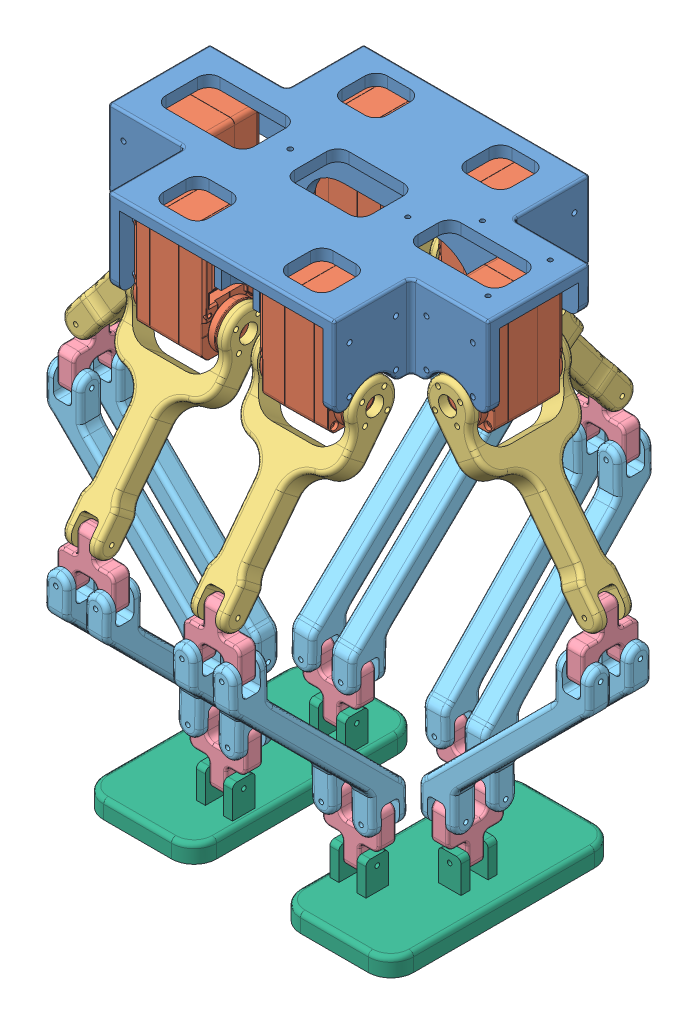
SolidWorks assembly bluebody-urdf, configuration Default. Lengths in mm.
Overall size (254.56 248.23 199.52).
42 component instances, 6 part files, 75 mates.
Components (placement in the parent):
- link0-1: link0 [Default] x (1 0 0) z (0 0 -1) size (168 59.68 113)
  - platform-v4-1: platform-v4 [Default] at (0 36.8 -17.5) x (-1 0 0) z (0 0 1) size (168 36.8 113)
  - Servo-LX-16A-1: Servo-LX-16A [Default] at (37.5 14.825 39.5) x (0 -1 0) z (0 0 1) size (54.66 37.3 26.46)
  - Servo-LX-16A-2: Servo-LX-16A [Default] at (-37.5 14.825 39.5) x (0 -1 0) z (0 0 -1) size (54.66 37.3 26.46)
  - Servo-LX-16A-3: Servo-LX-16A [Default] at (-67 14.825 -10) x (0 -1 0) z (1 0 0) size (54.66 37.3 26.46)
  - Servo-LX-16A-4: Servo-LX-16A [Default] at (-37.5 14.825 -39.5) x (0 -1 0) z (0 0 -1) size (54.66 37.3 26.46)
  - Servo-LX-16A-5: Servo-LX-16A [Default] at (37.5 14.825 -39.5) x (0 -1 0) z (0 0 1) size (54.66 37.3 26.46)
  - Servo-LX-16A-6: Servo-LX-16A [Default] at (67 14.825 -10) x (0 -1 0) z (1 0 0) size (54.66 37.3 26.46)
- link1-1: link1 [Default] at (27.9 -74.503 60.6628) x (0 0.793607 -0.60843) z (1 0 0) size (96 20 46.12)
- link1-2: link1 [Default] at (88.1738 -74.4962 0.4) x (-0.608687 0.793411 0) z (0 0 -1) size (96 20 46.12)
- link1-3: link1 [Default] at (27.9 -74.503 -60.6628) x (0 0.793607 0.60843) z (-1 0 0) size (96 20 46.12)
- link1-4: link1 [Default] at (-27.9 -74.503 -60.6628) x (0 0.793607 0.60843) z (-1 0 0) size (96 20 46.12)
- link1-5: link1 [Default] at (-88.1738 -74.4962 0.4) x (0.608687 0.793411 0) z (0 0 1) size (96 20 46.12)
- link1-6: link1 [Default] at (-27.9 -74.503 60.6628) x (0 0.793607 -0.60843) z (1 0 0) size (96 20 46.12)
- link2-1: link2 [Default] at (27.9 -108.2473 85) x (1 0 0) z (0 0 -1) size (25.2 28 7.6)
- link2-2: link2 [Default] at (112.5213 -108.2326 0.4) x (0 0 1) z (1 0 0) size (25.2 28 7.6)
- link2-3: link2 [Default] at (27.9 -108.2473 -85) x (1 0 0) z (0 0 -1) size (25.2 28 7.6)
- link2-4: link2 [Default] at (-27.9 -108.2473 -85) x (1 0 0) z (0 0 -1) size (25.2 28 7.6)
- link2-5: link2 [Default] at (-112.5213 -108.2326 0.4) x (0 0 -1) z (-1 0 0) size (25.2 28 7.6)
- link2-6: link2 [Default] at (-27.9 -108.2473 85) x (1 0 0) z (0 0 -1) size (25.2 28 7.6)
- link3-1: link3 [Default] at (14.9116 -168.336 55) x (0 0 -1) z (0.999814 0.019301 0) size (76 94 10)
- link3-2: link3 [Default] at (32.5116 -168.336 55) x (0 0 1) z (0.999814 0.019301 0) size (76 94 10)
- link3-3: link3 [Default] at (82.5213 -168.2559 13.9999) x (-1 0 0) z (0 0.004762 -0.999989) size (76 94 10)
- link3-4: link3 [Default] at (82.5213 -168.2559 -3.6001) x (1 0 0) z (0 0.004762 -0.999989) size (76 94 10)
- link3-5: link3 [Default] at (42.5097 -168.143 -55) x (0 0 -1) z (-0.999814 -0.019301 0) size (76 94 10)
- link3-6: link3 [Default] at (24.9097 -168.143 -55) x (0 0 -1) z (-0.999814 -0.019301 0) size (76 94 10)
- link3-7: link3 [Default] at (-14.9116 -168.336 -55) x (0 0 1) z (-0.999814 0.019301 0) size (76 94 10)
- link3-8: link3 [Default] at (-32.5116 -168.336 -55) x (0 0 1) z (-0.999814 0.019301 0) size (76 94 10)
- link3-9: link3 [Default] at (-82.5213 -168.2083 -13.5999) x (1 0 0) z (0 -0.004762 0.999989) size (76 94 10)
- link3-10: link3 [Default] at (-82.5213 -168.2083 4.0001) x (1 0 0) z (0 -0.004762 0.999989) size (76 94 10)
- link3-11: link3 [Default] at (-42.5097 -168.143 55) x (0 0 -1) z (0.999814 -0.019301 0) size (76 94 10)
- link3-12: link3 [Default] at (-24.9097 -168.143 55) x (0 0 -1) z (0.999814 -0.019301 0) size (76 94 10)
- bluefeet-1: bluefeet [Default] at (43.5213 -248.2317 0) x (0 0 -1) z (1 0 0) size (100 41.94 54.92) (flexible)
  - feet-1: feet [Default] at origin size (100 22 50)
  - link2-1: link2 [Default] at (-25 20 -14) x (0 0 -1) z (1 0 0) size (25.2 28 7.6)
  - link2-2: link2 [Default] at (0 20 9) size (25.2 28 7.6)
  - link2-3: link2 [Default] at (25 20 -14) x (0 0 -1) z (1 0 0) size (25.2 28 7.6)
- bluefeet-2: bluefeet [Default] at (-43.5213 -248.2317 0) x (0 0 1) z (-1 0 0) size (100 41.94 54.92) (flexible)
  - feet-1: feet [Default] at origin size (100 22 50)
  - link2-1: link2 [Default] at (-25 20 -14) x (0 0 -1) z (1 0 0) size (25.2 28 7.6)
  - link2-2: link2 [Default] at (0 20 9) size (25.2 28 7.6)
  - link2-3: link2 [Default] at (25 20 -14) x (0 0 -1) z (1 0 0) size (25.2 28 7.6)
Mates (geometry in assembly coordinates):
- Coincident1: coincident aligned: plane of link0-1/platform-v4-1 through (0 0 17.5) normal (0 1 0)
- Coincident2: coincident anti-aligned: plane of link0-1/platform-v4-1 through (0 -36.8 17.5) normal (-1 0 0)
- Coincident4: coincident anti-aligned: plane of link0-1/platform-v4-1 through (0 -36.8 0) normal (0 0 -1)
- Concentric1: concentric aligned: cylinder of link0-1/Servo-LX-16A-5 through (46.6 -40.325 39.5) axis (1 0 0) radius 10; cylinder of link1-1 through (4.9 -40.325 39.5) axis (1 0 0) radius 4
- Distance1: distance = 0.9 mm anti-aligned: plane of link0-1/Servo-LX-16A-5 through (46 -29.3267 39.5) normal (1 0 0); plane of link1-1 through (46.9 -60.5091 78.9158) normal (-1 0 0)
- Concentric2: concentric anti-aligned: cylinder of link0-1/Servo-LX-16A-6 through (67 -40.325 -14.6) axis (0 0 1) radius 10; cylinder of link1-2 through (67 -40.325 23.4) axis (0 0 -1) radius 4
- Distance2: distance = 0.9 mm anti-aligned: plane of link1-2 through (106.4223 -60.4964 -18.6) normal (0 0 1); plane of link0-1/Servo-LX-16A-6 through (86.9 -79.4276 -17.7) normal (0 0 -1)
- Concentric3: concentric anti-aligned: cylinder of link0-1/Servo-LX-16A-1 through (46.6 -40.325 -39.5) axis (1 0 0) radius 10; cylinder of link1-3 through (50.9 -40.325 -39.5) axis (-1 0 0) radius 4
- Distance3: distance = 0.9 mm anti-aligned: plane of link1-3 through (8.9 -60.5091 -78.9158) normal (1 0 0); plane of link0-1/Servo-LX-16A-1 through (9.8 -79.4276 -59.4) normal (-1 0 0)
- Concentric4: concentric aligned: cylinder of link0-1/Servo-LX-16A-2 through (-46.6 -40.325 -39.5) axis (-1 0 0) radius 10; cylinder of link1-4 through (-4.9 -40.325 -39.5) axis (-1 0 0) radius 4
- Distance4: distance = 0.9 mm anti-aligned: plane of link1-4 through (-8.9 -60.5091 -78.9158) normal (-1 0 0); plane of link0-1/Servo-LX-16A-2 through (-9.8 -79.4276 -19.6) normal (1 0 0)
- Concentric5: concentric aligned: cylinder of link0-1/Servo-LX-16A-3 through (-67 -40.325 19.1) axis (0 0 1) radius 10; cylinder of link1-5 through (-67 -40.325 -22.6) axis (0 0 1) radius 4
- Distance5: distance = 0.9 mm anti-aligned: plane of link1-5 through (-106.4223 -60.4964 -18.6) normal (0 0 1); plane of link0-1/Servo-LX-16A-3 through (-47.1 -79.4276 -17.7) normal (0 0 -1)
- Concentric6: concentric anti-aligned: cylinder of link1-6 through (-50.9 -40.325 39.5) axis (1 0 0) radius 4; cylinder of link0-1/Servo-LX-16A-4 through (-46.6 -40.325 39.5) axis (-1 0 0) radius 10
- Distance6: distance = 0.9 mm anti-aligned: plane of link1-6 through (-8.9 -60.5091 78.9158) normal (-1 0 0); plane of link0-1/Servo-LX-16A-4 through (-9.8 -79.4276 59.4) normal (1 0 0)
- Concentric7: concentric aligned: cylinder of link1-1 through (4.9 -106.2473 85) axis (1 0 0) radius 1; cylinder of link2-1 through (24.1 -106.2473 85) axis (1 0 0) radius 1.15
- Distance7: distance = 0.2 mm anti-aligned: plane of link2-1 through (31.7 -108.2473 88.8) normal (1 0 0); plane of link1-1 through (31.9 -60.5091 78.9158) normal (-1 0 0)
- Concentric8: concentric anti-aligned: cylinder of link1-2 through (112.5213 -106.2326 23.4) axis (0 0 -1) radius 1; cylinder of link2-2 through (112.5213 -106.2326 -3.4) axis (0 0 1) radius 1.15
- Distance8: distance = 0.2 mm anti-aligned: plane of link2-2 through (108.7213 -108.2326 -3.4) normal (0 0 -1); plane of link1-2 through (106.4223 -60.4964 -3.6) normal (0 0 1)
- Concentric9: concentric anti-aligned: cylinder of link1-3 through (50.9 -106.2473 -85) axis (-1 0 0) radius 1; cylinder of link2-3 through (24.1 -106.2473 -85) axis (1 0 0) radius 1.15
- Distance9: distance = 0.2 mm anti-aligned: plane of link2-3 through (31.7 -108.2473 -81.2) normal (1 0 0); plane of link1-3 through (31.9 -60.5091 -78.9158) normal (-1 0 0)
- Concentric10: concentric anti-aligned: cylinder of link1-4 through (-4.9 -106.2473 -85) axis (-1 0 0) radius 1; cylinder of link2-4 through (-31.7 -106.2473 -85) axis (1 0 0) radius 1.15
- Distance10: distance = 0.2 mm anti-aligned: plane of link2-4 through (-31.7 -108.2473 -81.2) normal (-1 0 0); plane of link1-4 through (-31.9 -60.5091 -78.9158) normal (1 0 0)
- Concentric11: concentric anti-aligned: cylinder of link1-5 through (-112.5213 -106.2326 -22.6) axis (0 0 1) radius 1; cylinder of link2-5 through (-112.5213 -106.2326 4.2) axis (0 0 -1) radius 1.15
- Distance11: distance = 0.2 mm anti-aligned: plane of link2-5 through (-108.7213 -108.2326 -3.4) normal (0 0 -1); plane of link1-5 through (-106.4223 -60.4964 -3.6) normal (0 0 1)
- Concentric12: concentric aligned: cylinder of link1-6 through (-50.9 -106.2473 85) axis (1 0 0) radius 1; cylinder of link2-6 through (-31.7 -106.2473 85) axis (1 0 0) radius 1.15
- Distance12: distance = 0.2 mm anti-aligned: plane of link2-6 through (-31.7 -108.2473 88.8) normal (-1 0 0); plane of link1-6 through (-31.9 -60.5091 78.9158) normal (1 0 0)
- Concentric13: concentric aligned: cylinder of link2-1 through (19.1 -126.2473 88.8) axis (0 0 -1) radius 1.15; cylinder of link3-1 through (19.1 -126.2473 93) axis (0 0 -1) radius 1
- Distance13: distance = 0.2 mm anti-aligned: plane of link3-1 through (24.9097 -168.143 89) normal (0 0 -1); plane of link2-1 through (27.9 -108.2473 88.8) normal (0 0 1)
- Concentric14: concentric anti-aligned: cylinder of link3-2 through (36.7 -126.2473 77) axis (0 0 1) radius 1; cylinder of link2-1 through (36.7 -126.2473 88.8) axis (0 0 -1) radius 1.15
- Distance14: distance = 0.2 mm anti-aligned: plane of link3-2 through (42.5097 -168.143 89) normal (0 0 -1); plane of link2-1 through (27.9 -108.2473 88.8) normal (0 0 1)
- Concentric15: concentric anti-aligned: cylinder of link2-2 through (108.7213 -126.2326 9.2) axis (1 0 0) radius 1.15; cylinder of link3-3 through (120.5213 -126.2326 9.2) axis (-1 0 0) radius 1
- Distance15: distance = 0.2 mm anti-aligned: plane of link3-3 through (116.5213 -168.2083 4.0001) normal (-1 0 0); plane of link2-2 through (116.3213 -108.2326 0.4) normal (1 0 0)
- Concentric16: concentric aligned: cylinder of link2-2 through (108.7213 -126.2326 -8.4) axis (1 0 0) radius 1.15; cylinder of link3-4 through (104.5213 -126.2326 -8.4) axis (1 0 0) radius 1
- Distance16: distance = 0.2 mm anti-aligned: plane of link3-4 through (116.5213 -168.2083 -13.5999) normal (-1 0 0); plane of link2-2 through (116.3213 -108.2326 0.4) normal (1 0 0)
- Concentric17: concentric aligned: cylinder of link3-6 through (19.1 -126.2473 -77) axis (0 0 -1) radius 1; cylinder of link2-3 through (19.1 -126.2473 -81.2) axis (0 0 -1) radius 1.15
- Distance17: distance = 0.2 mm anti-aligned: plane of link3-6 through (14.9116 -168.336 -89) normal (0 0 1); plane of link2-3 through (27.9 -108.2473 -88.8) normal (0 0 -1)
- Concentric18: concentric aligned: cylinder of link3-5 through (36.7 -126.2473 -77) axis (0 0 -1) radius 1; cylinder of link2-3 through (36.7 -126.2473 -81.2) axis (0 0 -1) radius 1.15
- Distance18: distance = 0.2 mm anti-aligned: plane of link3-5 through (32.5116 -168.336 -89) normal (0 0 1); plane of link2-3 through (27.9 -108.2473 -88.8) normal (0 0 -1)
- Concentric19: concentric anti-aligned: cylinder of link2-4 through (-19.1 -126.2473 -81.2) axis (0 0 -1) radius 1.15; cylinder of link3-7 through (-19.1 -126.2473 -93) axis (0 0 1) radius 1
- Distance19: distance = 0.2 mm anti-aligned: plane of link3-7 through (-24.9097 -168.143 -81) normal (0 0 -1); plane of link2-4 through (-27.9 -108.2473 -81.2) normal (0 0 1)
- Concentric20: concentric anti-aligned: cylinder of link2-4 through (-36.7 -126.2473 -81.2) axis (0 0 -1) radius 1.15; cylinder of link3-8 through (-36.7 -126.2473 -93) axis (0 0 1) radius 1
- Distance20: distance = 0.2 mm anti-aligned: plane of link3-8 through (-42.5097 -168.143 -81) normal (0 0 -1); plane of link2-4 through (-27.9 -108.2473 -81.2) normal (0 0 1)
- Concentric21: concentric anti-aligned: cylinder of link2-5 through (-108.7213 -126.2326 -8.4) axis (-1 0 0) radius 1.15; cylinder of link3-9 through (-120.5213 -126.2326 -8.4) axis (1 0 0) radius 1
- Distance21: distance = 0.2 mm anti-aligned: plane of link3-9 through (-108.5213 -168.2559 -3.6001) normal (-1 0 0); plane of link2-5 through (-108.7213 -108.2326 0.4) normal (1 0 0)
- Concentric22: concentric anti-aligned: cylinder of link2-5 through (-108.7213 -126.2326 9.2) axis (-1 0 0) radius 1.15; cylinder of link3-10 through (-120.5213 -126.2326 9.2) axis (1 0 0) radius 1
- Distance22: distance = 0.2 mm anti-aligned: plane of link3-10 through (-108.5213 -168.2559 13.9999) normal (-1 0 0); plane of link2-5 through (-108.7213 -108.2326 0.4) normal (1 0 0)
- Concentric23: concentric aligned: cylinder of link2-6 through (-36.7 -126.2473 88.8) axis (0 0 -1) radius 1.15; cylinder of link3-11 through (-36.7 -126.2473 93) axis (0 0 -1) radius 1
- Distance23: distance = 0.2 mm anti-aligned: plane of link3-11 through (-32.5116 -168.336 81) normal (0 0 1); plane of link2-6 through (-27.9 -108.2473 81.2) normal (0 0 -1)
- Concentric24: concentric aligned: cylinder of link2-6 through (-19.1 -126.2473 88.8) axis (0 0 -1) radius 1.15; cylinder of link3-12 through (-19.1 -126.2473 93) axis (0 0 -1) radius 1
- Distance24: distance = 0.2 mm anti-aligned: plane of link3-12 through (-14.9116 -168.336 81) normal (0 0 1); plane of link2-6 through (-27.9 -108.2473 81.2) normal (0 0 -1)
- Concentric29: concentric aligned: cylinder of link3-4 through (44.5213 -210.2317 -8.8) axis (1 0 0) radius 1; cylinder of bluefeet-1/link2-2 through (48.7213 -210.2317 -8.8) axis (1 0 0) radius 1.15
- Distance26: distance = 0.2 mm anti-aligned: plane of bluefeet-1/link2-2 through (56.3213 -228.2317 0) normal (1 0 0); plane of link3-4 through (56.5213 -168.2083 -13.5999) normal (-1 0 0)
- Concentric30: concentric anti-aligned: cylinder of link3-3 through (60.5213 -210.2317 8.8) axis (-1 0 0) radius 1; cylinder of bluefeet-1/link2-2 through (48.7213 -210.2317 8.8) axis (1 0 0) radius 1.15
- Concentric31: concentric anti-aligned: cylinder of link3-2 through (38.3213 -210.2317 17) axis (0 0 1) radius 1; cylinder of bluefeet-1/link2-1 through (38.3213 -210.2317 28.8) axis (0 0 -1) radius 1.15
- Distance27: distance = 0.2 mm anti-aligned: plane of link3-2 through (42.5097 -168.143 29) normal (0 0 -1); plane of bluefeet-1/link2-1 through (29.5213 -228.2317 28.8) normal (0 0 1)
- Concentric32: concentric aligned: cylinder of link3-1 through (20.7213 -210.2317 33) axis (0 0 -1) radius 1; cylinder of bluefeet-1/link2-1 through (20.7213 -210.2317 28.8) axis (0 0 -1) radius 1.15
- Concentric33: concentric aligned: cylinder of link3-5 through (38.3213 -210.2317 -17) axis (0 0 -1) radius 1; cylinder of bluefeet-1/link2-3 through (38.3213 -210.2317 -21.2) axis (0 0 -1) radius 1.15
- Distance28: distance = 0.2 mm anti-aligned: plane of bluefeet-1/link2-3 through (29.5213 -228.2317 -28.8) normal (0 0 -1); plane of link3-5 through (32.5116 -168.336 -29) normal (0 0 1)
- Concentric34: concentric aligned: cylinder of link3-6 through (20.7213 -210.2317 -17) axis (0 0 -1) radius 1; cylinder of bluefeet-1/link2-3 through (20.7213 -210.2317 -21.2) axis (0 0 -1) radius 1.15
- Concentric35: concentric anti-aligned: cylinder of link3-9 through (-60.5213 -210.2317 -8.8) axis (1 0 0) radius 1; cylinder of bluefeet-2/link2-2 through (-48.7213 -210.2317 -8.8) axis (-1 0 0) radius 1.15
- Distance29: distance = 0.2 mm anti-aligned: plane of bluefeet-2/link2-2 through (-56.3213 -228.2317 0) normal (-1 0 0); plane of link3-9 through (-56.5213 -168.2559 -3.6001) normal (1 0 0)
- Concentric36: concentric anti-aligned: cylinder of link3-10 through (-60.5213 -210.2317 8.8) axis (1 0 0) radius 1; cylinder of bluefeet-2/link2-2 through (-48.7213 -210.2317 8.8) axis (-1 0 0) radius 1.15
- Concentric37: concentric aligned: cylinder of link3-8 through (-38.3213 -210.2317 -33) axis (0 0 1) radius 1; cylinder of bluefeet-2/link2-1 through (-38.3213 -210.2317 -28.8) axis (0 0 1) radius 1.15
- Distance30: distance = 0.2 mm anti-aligned: plane of bluefeet-2/link2-1 through (-29.5213 -228.2317 -28.8) normal (0 0 -1); plane of link3-8 through (-42.5097 -168.143 -29) normal (0 0 1)
- Concentric38: concentric aligned: cylinder of link3-7 through (-20.7213 -210.2317 -33) axis (0 0 1) radius 1; cylinder of bluefeet-2/link2-1 through (-20.7213 -210.2317 -28.8) axis (0 0 1) radius 1.15
- Concentric39: concentric anti-aligned: cylinder of link3-11 through (-38.3213 -210.2317 33) axis (0 0 -1) radius 1; cylinder of bluefeet-2/link2-3 through (-38.3213 -210.2317 21.2) axis (0 0 1) radius 1.15
- Distance31: distance = 0.2 mm anti-aligned: plane of link3-11 through (-32.5116 -168.336 29) normal (0 0 -1); plane of bluefeet-2/link2-3 through (-29.5213 -228.2317 28.8) normal (0 0 1)
- Concentric40: concentric anti-aligned: cylinder of link3-12 through (-20.7213 -210.2317 33) axis (0 0 -1) radius 1; cylinder of bluefeet-2/link2-3 through (-20.7213 -210.2317 21.2) axis (0 0 1) radius 1.15
- Parallel3: parallel aligned: plane of link0-1/platform-v4-1 through (84 -5 -17.5) normal (1 0 0); plane of link2-2 through (116.3213 -108.2326 0.4) normal (1 0 0)
- Parallel4: parallel aligned: plane of link0-1/platform-v4-1 through (-50 -5 -56.5) normal (0 0 -1); plane of link2-3 through (27.9 -108.2473 -88.8) normal (0 0 -1)
- Parallel5: parallel aligned: plane of link0-1/platform-v4-1 through (50 0 56.5) normal (0 0 1); plane of link2-1 through (27.9 -108.2473 88.8) normal (0 0 1)
- Parallel6: parallel aligned: plane of link0-1/platform-v4-1 through (-84 -5 -17.5) normal (-1 0 0); plane of link2-5 through (-116.3213 -108.2326 0.4) normal (-1 0 0)
- Parallel7: parallel aligned: plane of link0-1/platform-v4-1 through (-50 -5 -56.5) normal (0 0 -1); plane of link2-4 through (-27.9 -108.2473 -88.8) normal (0 0 -1)
- Parallel8: parallel aligned: plane of link2-6 through (-27.9 -108.2473 88.8) normal (0 0 1); plane of link0-1/platform-v4-1 through (50 0 56.5) normal (0 0 1)
